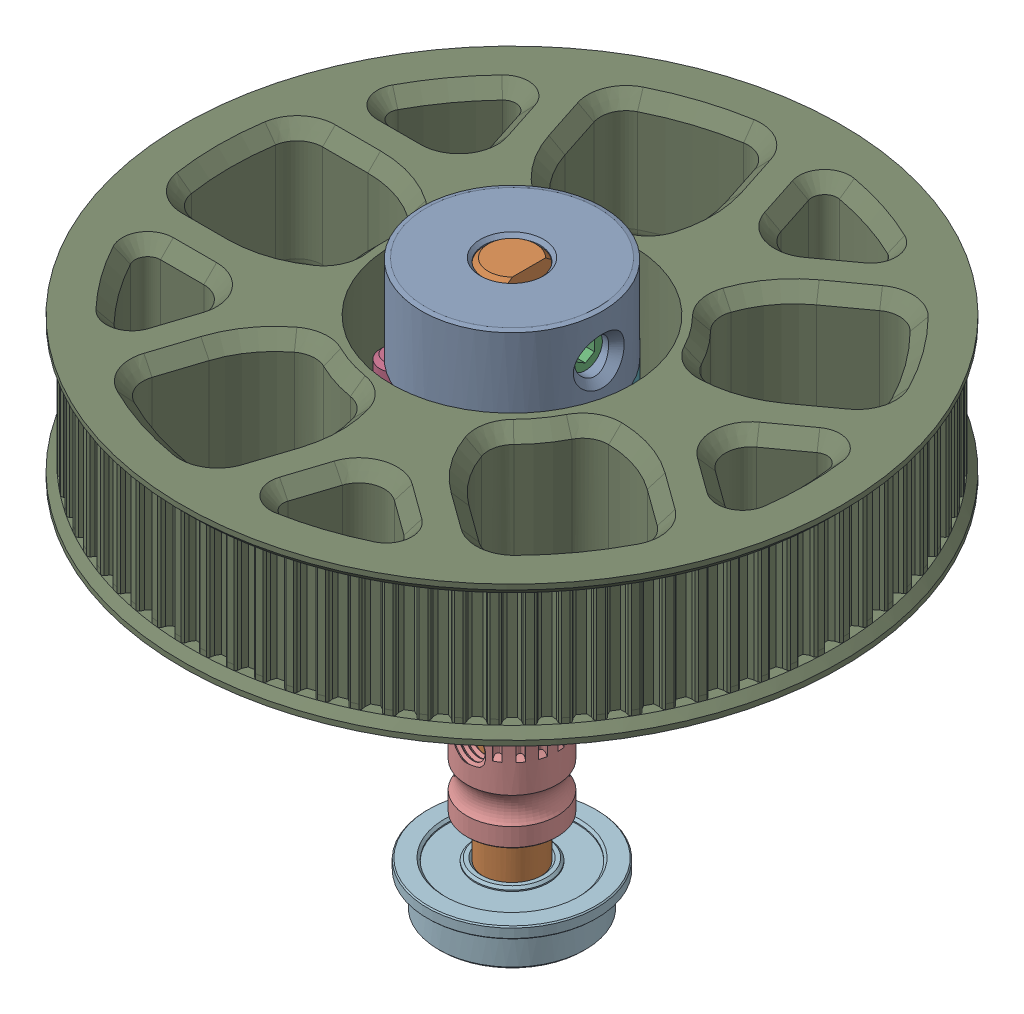
SolidWorks assembly Mobius Extruder Core, configuration Varsayılan. Lengths in mm.
Overall size (58.34 50 58.34).
14 component instances, 8 part files, 0 mates.
Components (placement in the parent):
- 80T Gear v1-1: 80T Gear v1 [Varsayılan] at (-81.1624 48.3497 29.8481) x (1 0 0) z (0 1 0) size (58.34 58.34 17.85)
  - GT2 20T 6mm Powge v2 (1)-1: GT2 20T 6mm Powge v2 (1) [Varsayılan] at (-0.0006 -0.0003 11.2993) x (0 0 -1) z (1 0 0) size (16 16 16)
  - M3x8 BHCS-1: M3x8 BHCS [Varsayılan] at (-5.9041 -4.2895 -6.5507) x (-1 0 0) z (0 0 -1) size (5.7 5.7 9.65)
  - M3x8 BHCS-2: M3x8 BHCS [Varsayılan] at (2.2544 -6.9404 -6.5507) x (-0.309017 -0.951057 0) z (0 0 -1) size (5.7 5.7 9.65)
  - M3x8 BHCS-3: M3x8 BHCS [Varsayılan] at (7.2966 -0.0003 -6.5507) x (0.809017 -0.587785 0) z (0 0 -1) size (5.7 5.7 9.65)
  - M3x8 BHCS-4: M3x8 BHCS [Varsayılan] at (2.2544 6.9397 -6.5507) x (0.809017 0.587785 0) z (0 0 -1) size (5.7 5.7 9.65)
  - M3x8 BHCS-5: M3x8 BHCS [Varsayılan] at (-5.9041 4.2888 -6.5507) x (-0.309017 0.951057 0) z (0 0 -1) size (5.7 5.7 9.65)
  - 80T Gear v1-0-1: 80T Gear v1-0 [Varsayılan] at origin size (58.34 58.34 12.51)
- Bondtech Drive gear-1: Bondtech Drive gear [Varsayılan] at (-81.163 38.849 29.8484) x (0 0 -1) z (1 0 0) size (9.49 14 9.55)
- F695 2RS-1: F695 2RS [Varsayılan] at (-81.163 35.449 29.8484) x (0 0 -1) z (1 0 0) size (15 4 15)
- F695 2RS-2: F695 2RS [Varsayılan] at (-81.163 13.649 29.8484) x (0 0 1) z (1 0 0) size (15 4 15)
- M5x1 Washer-1: M5x1 Washer [Varsayılan] at (-81.163 38.549 29.8484) x (1 0 0) z (0 1 0) size (10 10 1)
- 5x48mm Shaft-1: 5x48mm Shaft [Varsayılan] at (0 22.15 -0.0007) x (0 -1 0) z (1 0 0) size (50 5 5)
- 5x4mm spacer-1: 5x4mm spacer [Varsayılan] at (-81.163 8.149 29.8484) x (0 -1 0) z (1 0 0) size (4 8.4 8.4)
